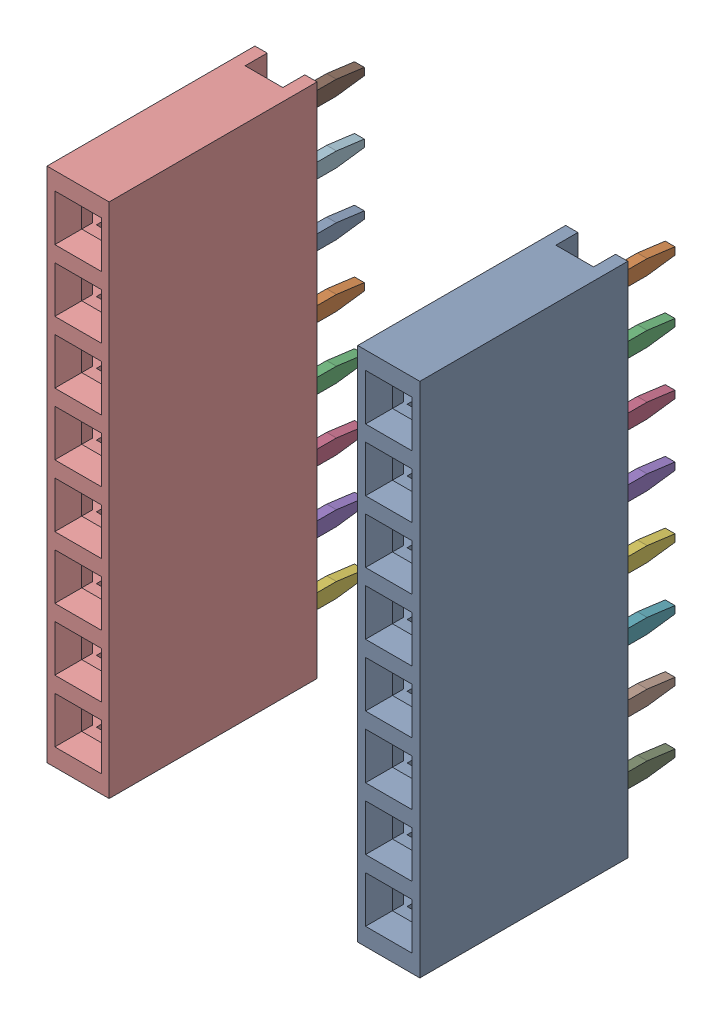
SolidWorks assembly X, configuration 默认. Lengths in mm.
Overall size (15.24 21.12 11.5).
2 component instances, 1 part files, 0 mates.
Components (placement in the parent):
- DS1023-1x8SF11-1: DS1023-1x8SF11 [默认] at (13.9593 19.0061 0) x (0 -1 0) z (0 0 1) size (21.12 2.54 11.5)
- DS1023-1x8SF11-2: DS1023-1x8SF11 [默认] at (1.2593 19.0061 0) x (0 -1 0) z (0 0 1) size (21.12 2.54 11.5)
